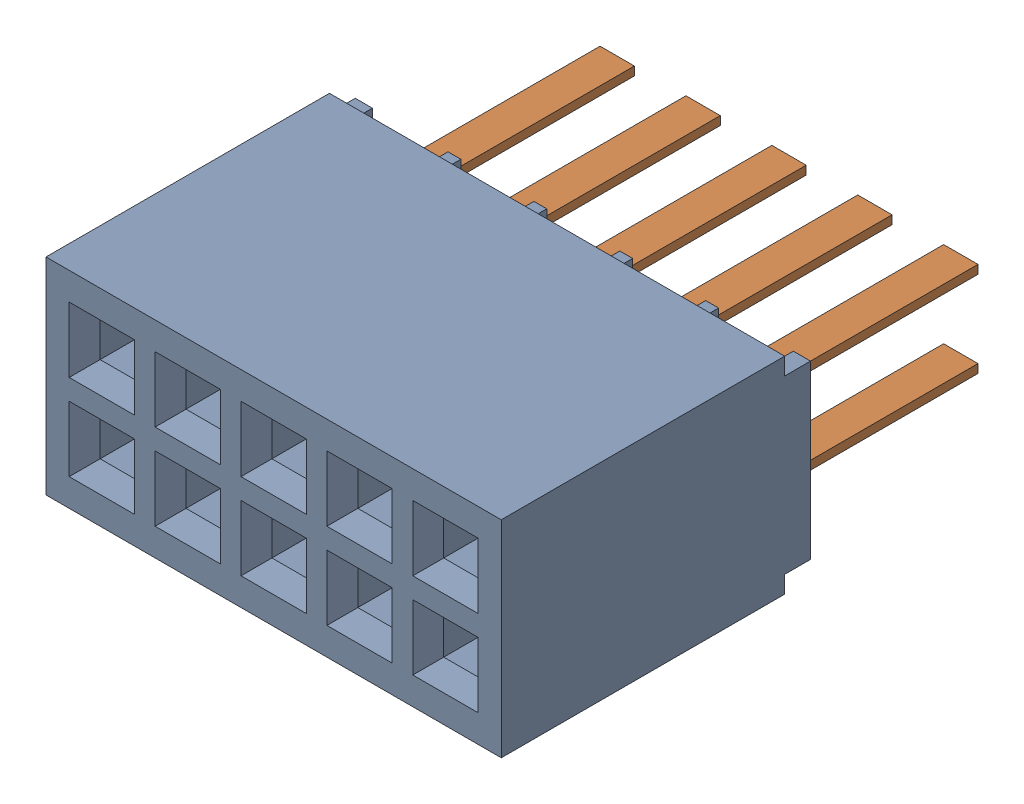
SolidWorks assembly J3, configuration ﾃﾞﾌｫﾙﾄ. Lengths in mm.
Overall size (6.73 3.05 7.62).
3 component instances, 2 part files, 0 mates.
Components (placement in the parent):
- SFMC-105-01-S-D-1: SFMC-105-01-S-D [ﾃﾞﾌｫﾙﾄ] at (9.34 40.97 0) x (-1 0 0) z (0 1 0) size (6.73 7.62 3.05)
  - _SFMC-105-01_socket-1: _SFMC-105-01_socket [ﾃﾞﾌｫﾙﾄ] at origin size (6.73 4.57 3.05)
  - _C-05-01_spins-1: _C-05-01_spins [ﾃﾞﾌｫﾙﾄ] at origin size (5.59 3.81 1.78)
